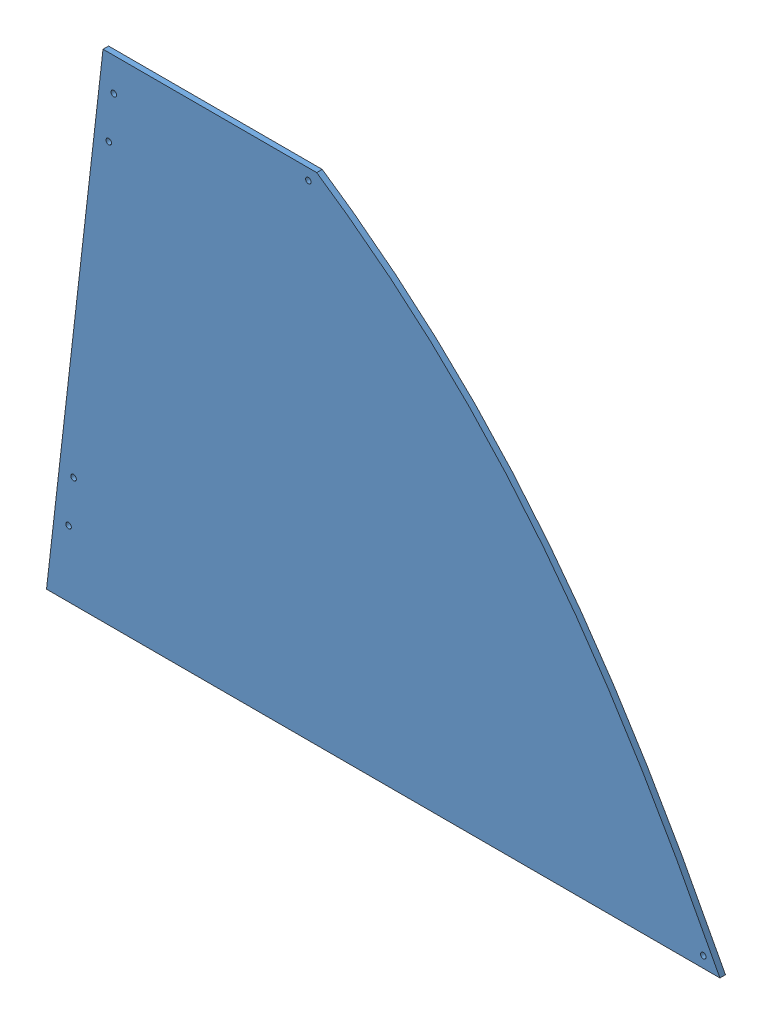
SolidWorks assembly GE-19080-Left-Red, configuration Default. Lengths in mm.
Overall size (771.1 567.83 44.58).
2 component instances, 2 part files, 3 mates.
Components (placement in the parent):
- GE-19080-1: GE-19080 [GE-19080] at origin size (771.1 567.83 6.35)
- GE-19080-Left-Red-Vinyl-1: GE-19080-Left-Red-Vinyl [Notched] at (0 0 -0.127) size (771.1 567.83 0.13)
Mates (geometry in assembly coordinates):
- Coincident2: coincident: plane of assembly; plane of assembly; plane of GE-19080-1 through (64.6956 567.8263 6.35) normal (0 1 0); plane of GE-19080-Left-Red-Vinyl-1 through (64.6956 567.8263 0) normal (0 1 0)
- Coincident3: coincident: plane of assembly; plane of assembly; plane of GE-19080-1 through (32.7402 567.8263 582.3432) normal (-0.993572 0.113203 0); plane of GE-19080-Left-Red-Vinyl-1 through (32.7402 567.8263 575.9932) normal (-0.993572 0.113203 0)
- Coincident4: coincident: plane of assembly; plane of assembly; plane of GE-19080-1 through (546.1766 314.686 0) normal (0 0 -1); plane of GE-19080-Left-Red-Vinyl-1 through (546.1766 314.686 0) normal (0 0 1)
